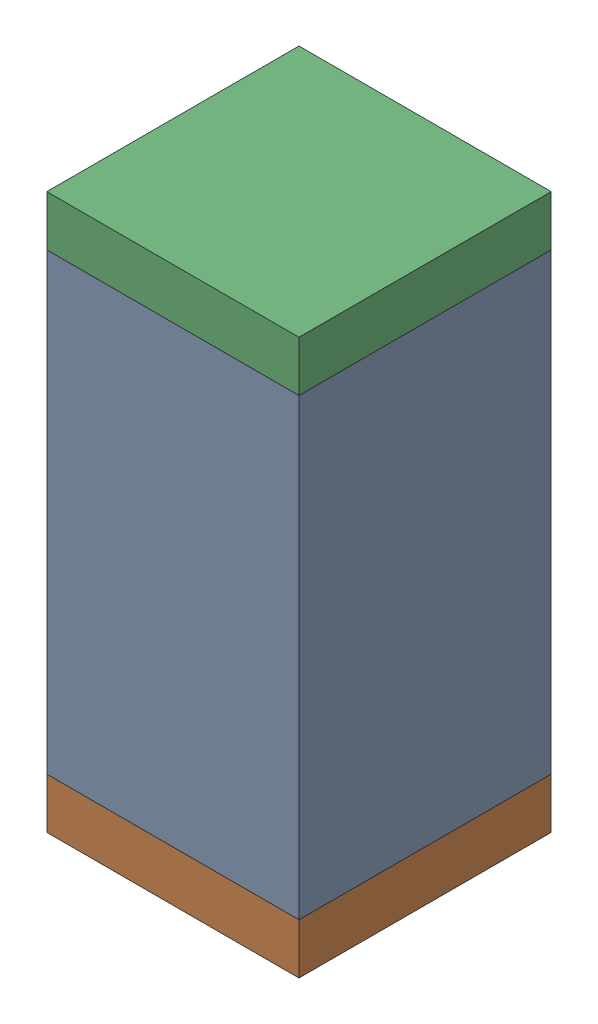
SolidWorks assembly C21, configuration Default. Lengths in mm.
Overall size (0.5 1.1 0.5).
6 component instances, 2 part files, 0 mates.
Components (placement in the parent):
- 791586336-1: 791586336 [Default] at (113.05 18.7 0) size (0.5 0.9 0.5)
  - Extruded_8-1: Extruded_8 [Default] at origin size (0.5 0.9 0.5)
- 810157360-1: 810157360 [Default] at (113.05 18.2 0) size (0.5 0.1 0.5)
  - Extruded_9-1: Extruded_9 [Default] at origin size (0.5 0.1 0.5)
- 810157360-2: 810157360 [Default] at (113.05 19.2 0) size (0.5 0.1 0.5)
  - Extruded_9-1: Extruded_9 [Default] at origin size (0.5 0.1 0.5)
